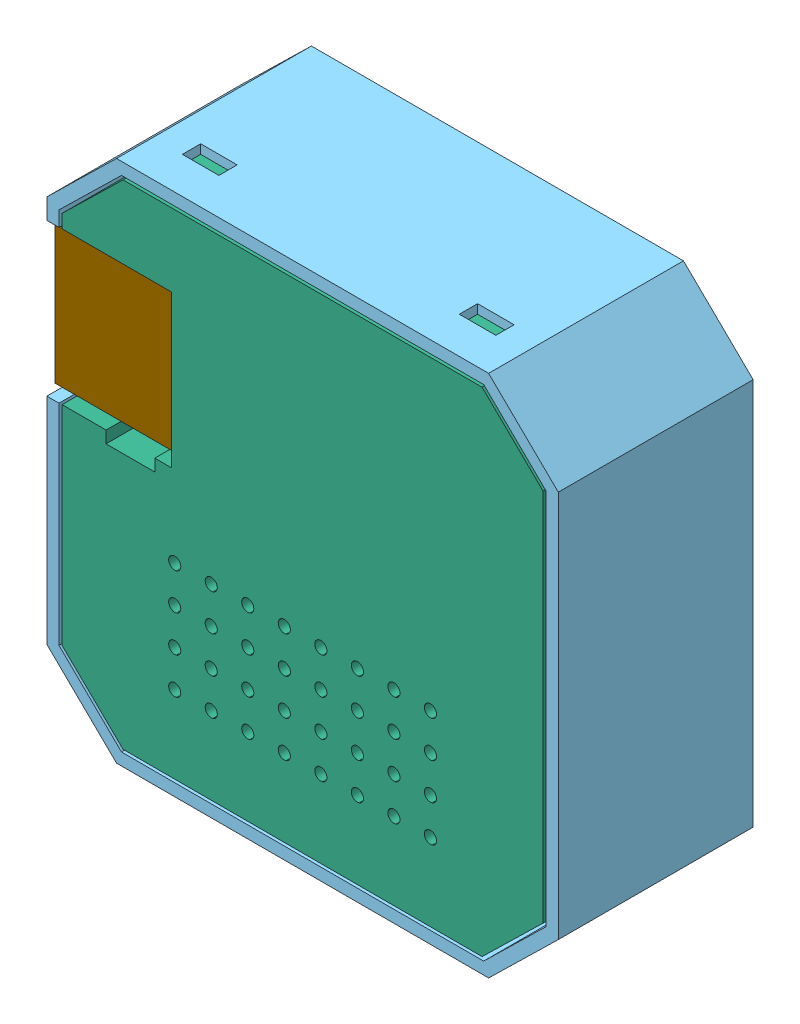
SolidWorks assembly UP-Buzzer-asm, configuration Default. Lengths in mm.
Overall size (42.12 43 16).
101 component instances, 61 part files, 8 mates.
Components (placement in the parent):
- UP1-Controller2040_V00.02.step-1: UP1-Controller2040_V00.02.step [Default] at (23.1746 53.0098 30.1469) size (40.62 22.3 14.2)
  - Board_Geoms_d6bd.step-1: Board_Geoms_d6bd.step [Default] at origin size (39 17.6 1.6)
    - Pcb_d6bd.step-1: Pcb_d6bd.step [Default] at (-120 80 0) size (39 17.6 1.6)
    - PCB_Sketch_d6bd.step-1: PCB_Sketch_d6bd.step [Default] at origin
  - Step_Models_d6bd.step-1: Step_Models_d6bd.step [Default] at origin size (39.5 21.08 14.2)
    - Top_d6bd.step-1: Top_d6bd.step [Default] at origin size (39.5 21.08 13.2)
      - J102_PinHeader_1x20_P127mm_Horizontal_60EE9F63.step-1: J102_PinHeader_1x20_P127mm_Horizontal_60EE9F63.step [Default] at (6.85 -37.8 -0.7) x (0 -1 0) z (0 0 1) size (5.7 25.4 4.5)
      - R111_R_0603_1608Metric_6205EFC4.step-1: R111_R_0603_1608Metric_6205EFC4.step [Default] at (-11 -34.6 0) x (0 1 0) z (0 0 1) size (1.6 0.8 0.45)
      - R112_R_0603_1608Metric_6205EFD5.step-1: R112_R_0603_1608Metric_6205EFD5.step [Default] at (-9.4 -34.6 0) x (0 1 0) z (0 0 1) size (1.6 0.8 0.45)
      - GN100_NanoBCU_V00.10_wo_headers_60EECF29.step-1: GN100_NanoBCU_V00.10_wo_headers_60EECF29.step [Default] at (0 -23.42 8.2) x (0 -1 0) z (0 0 1) size (18 18 8.65)
      - GN100_PinHeader_1x07_P254mm_Vertical_SMD_Pin1Left_60EECF29[2].step-1: GN100_PinHeader_1x07_P254mm_Vertical_SMD_Pin1Left_60EECF29[2].step [Default] at (-10.18 -24.72 0) x (0 1 0) z (0 0 1) size (5 17.78 9.3)
      - U102_SOT_23_5_6205ACC4.step-1: U102_SOT_23_5_6205ACC4.step [Default] at (-14.6 -34.5 0) x (0 1 0) z (0 0 1) size (2.8 2.9 1.55)
      - U103_SOT_23_6_6205A775.step-1: U103_SOT_23_6_6205A775.step [Default] at (-18.3 -34.5 0) x (0 1 0) z (0 0 1) size (2.8 2.9 1.55)
      - J100__243-212_60AF9738.step-1: J100__243-212_60AF9738.step [Default] at (-21.6186 -27.2 0.1) x (-1 0 0) z (0 0 1) size (10 12.61 10)
      - R114_R_0603_1608Metric_61113DD2.step-1: R114_R_0603_1608Metric_61113DD2.step [Default] at (-2.85 -34.25 0) x (-1 0 0) z (0 0 1) size (1.6 0.8 0.45)
      - R113_R_0603_1608Metric_61113DC1.step-1: R113_R_0603_1608Metric_61113DC1.step [Default] at (-2.855 -35.78 0) x (-1 0 0) z (0 0 1) size (1.6 0.8 0.45)
      - D100_D_SMA_60EECA5D.step-1: D100_D_SMA_60EECA5D.step [Default] at (-23 -24 0) size (5 2.7 2.22)
      - J101_PinHeader_1x08_P127mm_Vertical_60ECF3C0.step-1: J101_PinHeader_1x08_P127mm_Vertical_60ECF3C0.step [Default] at (6.83 -26.74 0) size (2.1 10.16 6.3)
    - Bot_d6bd.step-1: Bot_d6bd.step [Default] at origin size (33.8 14.77 2.55)
      - R109_R_0603_1608Metric_60F57743.step-1: R109_R_0603_1608Metric_60F57743.step [Default] at (-19.65 -36.325 -1.6) x (0 1 0) z (0 0 -1) size (1.6 0.8 0.45)
      - R110_R_0603_1608Metric_60F57732.step-1: R110_R_0603_1608Metric_60F57732.step [Default] at (-16.95 -35.425 -1.6) x (-1 0 0) z (0 0 -1) size (1.6 0.8 0.45)
      - R106_R_0402_1005Metric_60F519DA.step-1: R106_R_0402_1005Metric_60F519DA.step [Default] at (5.05 -33 -1.6) x (0 -1 0) z (0 0 -1) size (1 0.5 0.35)
      - U100_QFN-56-1EP_7x7mm_Pitch0.4mm_60ECE89B.step-1: U100_QFN-56-1EP_7x7mm_Pitch0.4mm_60ECE89B.step [Default] at (-6 -28.5 -1.6) x (0 -1 0) z (0 0 -1) size (7 7 0.92)
      - R115_R_0603_1608Metric_60ECF916.step-1: R115_R_0603_1608Metric_60ECF916.step [Default] at (2.5 -34.75 -1.6) x (1 0 0) z (0 0 -1) size (1.6 0.8 0.45)
      - R116_R_0603_1608Metric_60B1282C.step-1: R116_R_0603_1608Metric_60B1282C.step [Default] at (2.5 -36.25 -1.6) x (1 0 0) z (0 0 -1) size (1.6 0.8 0.45)
      - U101_SSOP_8_525x524mm_P127mm_60EDBF3D.step-1: U101_SSOP_8_525x524mm_P127mm_60EDBF3D.step [Default] at (-17.25 -28.25 -1.6) x (0 -1 0) z (0 0 -1) size (8.22 5.24 1.6)
      - Y100_Crystal_SMD_3225-4Pin_3.2x2.5mm_60EEB131.step-1: Y100_Crystal_SMD_3225-4Pin_3.2x2.5mm_60EEB131.step [Default] at (3.98 -26.43 -1.6) x (0 -1 0) z (0 0 -1) size (3.2 2.5 0.64)
      - SW100_SKRPACE010_v4_60ED873A.step-1: SW100_SKRPACE010_v4_60ED873A.step [Default] at (-25.8 -26.6 -1.6) x (1 0 0) z (0 1 0) size (4.89 2.55 3.2)
      - R105_C_0402_1005Metric_60ECE7EE.step-1: R105_C_0402_1005Metric_60ECE7EE.step [Default] at (-0.25 -32.25 -1.6) x (1 0 0) z (0 0 -1) size (1 0.5 0.5)
      - R108_C_0402_1005Metric_60ECE7DF.step-1: R108_C_0402_1005Metric_60ECE7DF.step [Default] at (-12 -31 -1.6) x (1 0 0) z (0 0 -1) size (1 0.5 0.5)
      - R107_C_0402_1005Metric_60ECE7D0.step-1: R107_C_0402_1005Metric_60ECE7D0.step [Default] at (-12 -30 -1.6) x (1 0 0) z (0 0 -1) size (1 0.5 0.5)
      - R102_C_0402_1005Metric_60ECE7C1.step-1: R102_C_0402_1005Metric_60ECE7C1.step [Default] at (1.62 -27.51 -1.6) x (0 1 0) z (0 0 -1) size (1 0.5 0.5)
      - R103_C_0402_1005Metric_60ECE7B2.step-1: R103_C_0402_1005Metric_60ECE7B2.step [Default] at (-0.25 -33.5 -1.6) x (1 0 0) z (0 0 -1) size (1 0.5 0.5)
      - R104_C_0402_1005Metric_60ECE7A3.step-1: R104_C_0402_1005Metric_60ECE7A3.step [Default] at (-10.71 -24.72 -1.6) x (0 -1 0) z (0 0 -1) size (1 0.5 0.5)
      - R101_R_0402_1005Metric_60ECE794.step-1: R101_R_0402_1005Metric_60ECE794.step [Default] at (-28.25 -28 -1.6) x (0 1 0) z (0 0 -1) size (1 0.5 0.35)
      - D101_LED_0603_1608Metric_60EEBCB9.step-1: D101_LED_0603_1608Metric_60EEBCB9.step [Default] at (-27.5 -32.5 -1.6) x (-1 0 0) z (0 0 -1) size (1.6 0.8 1.1)
      - C115_C_0402_1005Metric_60ECE606.step-1: C115_C_0402_1005Metric_60ECE606.step [Default] at (-9 -23.26 -1.6) x (0 1 0) z (0 0 -1) size (1 0.5 0.5)
      - C114_C_0402_1005Metric_60ECE5F7.step-1: C114_C_0402_1005Metric_60ECE5F7.step [Default] at (-4.5 -23 -1.6) x (0 1 0) z (0 0 -1) size (1 0.5 0.5)
      - C113_C_0402_1005Metric_60ECE5E8.step-1: C113_C_0402_1005Metric_60ECE5E8.step [Default] at (-0.25 -28.25 -1.6) x (1 0 0) z (0 0 -1) size (1 0.5 0.5)
      - C112_C_0402_1005Metric_60ECE5D9.step-1: C112_C_0402_1005Metric_60ECE5D9.step [Default] at (-4.925 -33.85 -1.6) x (0 -1 0) z (0 0 -1) size (1 0.5 0.5)
      - C111_C_0402_1005Metric_60EECFE7.step-1: C111_C_0402_1005Metric_60EECFE7.step [Default] at (-9.775 -34.15 -1.6) x (-1 0 0) z (0 0 -1) size (1 0.5 0.5)
      - C110_C_0402_1005Metric_60ECE5AC.step-1: C110_C_0402_1005Metric_60ECE5AC.step [Default] at (-12 -29 -1.6) x (-1 0 0) z (0 0 -1) size (1 0.5 0.5)
      - C120_C_0402_1005Metric_60EECFBD.step-1: C120_C_0402_1005Metric_60EECFBD.step [Default] at (-9.775 -33.15 -1.6) x (-1 0 0) z (0 0 -1) size (1 0.5 0.5)
      - C130_C_0402_1005Metric_60EEB37E.step-1: C130_C_0402_1005Metric_60EEB37E.step [Default] at (-11.075 -32 -1.6) x (-1 0 0) z (0 0 -1) size (1 0.5 0.5)
      - C131_C_0402_1005Metric_60ED72AC.step-1: C131_C_0402_1005Metric_60ED72AC.step [Default] at (-0.25 -29.25 -1.6) x (1 0 0) z (0 0 -1) size (1 0.5 0.5)
      - C132_C_0402_1005Metric_60ECE570.step-1: C132_C_0402_1005Metric_60ECE570.step [Default] at (-12 -28 -1.6) x (-1 0 0) z (0 0 -1) size (1 0.5 0.5)
      - C109_C_0805_2012Metric_60ECE561.step-1: C109_C_0805_2012Metric_60ECE561.step [Default] at (-1.85 -22.98 -1.6) x (1 0 0) z (0 0 -1) size (2 1.25 1.25)
      - C105_C_0402_1005Metric_60ECE550.step-1: C105_C_0402_1005Metric_60ECE550.step [Default] at (-0.25 -31.25 -1.6) x (-1 0 0) z (0 0 -1) size (1 0.5 0.5)
      - C101_C_0402_1005Metric_60ECE541.step-1: C101_C_0402_1005Metric_60ECE541.step [Default] at (3.98 -29.04 -1.6) x (1 0 0) z (0 0 -1) size (1 0.5 0.5)
      - C102_C_0402_1005Metric_60ECE532.step-1: C102_C_0402_1005Metric_60ECE532.step [Default] at (3.98 -23.79 -1.6) x (-1 0 0) z (0 0 -1) size (1 0.5 0.5)
      - C103_C_0402_1005Metric_60ECE523.step-1: C103_C_0402_1005Metric_60ECE523.step [Default] at (-19.2 -33.5 -1.6) x (1 0 0) z (0 0 -1) size (1 0.5 0.5)
- UP-Buzzer-PCB.step-1: UP-Buzzer-PCB.step [Default] at (-6.9323 10.7878 29.4969) x (0 -1 0) z (0 0 1) size (20.62 38.86 15.85)
  - Board.step-1: Board.step [Default] at origin size (18.8 38.86 1.69)
    - Open CASCADE STEP translator 7.5 1.1.1.step-1: Open CASCADE STEP translator 7.5 1.1.1.step [Default] at (0 0 -1.6916) size (18.8 38.86 1.69)
  - U2.step-1: U2.step [Default] at origin size (11.61 5.99 15.65) (hidden)
    - 6360212480.step-1: 6360212480.step [Default] at (3.3148 8.204 0) x (1 0 0) z (0 0 1) size (11.61 5.99 15.65)
  - R9.step-1: R9.step [Default] at origin size (0.81 1.6 0.71) (hidden)
    - 6360212240.step-1: 6360212240.step [Default] at (16.129 10.922 -1.6916) x (0 -1 0) z (0 0 -1) size (1.6 0.81 0.71)
  - R8.step-1: R8.step [Default] at origin size (0.81 1.6 0.71) (hidden)
    - 6360212240.step-1: 6360212240.step [Default] at (14.605 10.922 -1.6916) x (0 -1 0) z (0 0 -1) size (1.6 0.81 0.71)
  - R7.step-1: R7.step [Default] at origin size (0.81 1.6 0.71) (hidden)
    - 6360212240.step-1: 6360212240.step [Default] at (13.081 10.922 -1.6916) x (0 -1 0) z (0 0 -1) size (1.6 0.81 0.71)
  - R6.step-1: R6.step [Default] at origin size (0.81 1.6 0.71) (hidden)
    - 6360212240.step-1: 6360212240.step [Default] at (11.557 10.922 -1.6916) x (0 -1 0) z (0 0 -1) size (1.6 0.81 0.71)
  - R5.step-1: R5.step [Default] at origin size (0.81 1.6 0.71) (hidden)
    - 6360212240.step-1: 6360212240.step [Default] at (10.033 10.922 -1.6916) x (0 -1 0) z (0 0 -1) size (1.6 0.81 0.71)
  - R4.step-1: R4.step [Default] at origin size (0.81 1.6 0.71) (hidden)
    - 6360212240.step-1: 6360212240.step [Default] at (8.509 10.922 -1.6916) x (0 -1 0) z (0 0 -1) size (1.6 0.81 0.71)
  - R3.step-1: R3.step [Default] at origin size (0.81 1.6 0.71) (hidden)
    - 6360212240.step-1: 6360212240.step [Default] at (6.985 10.922 -1.6916) x (0 -1 0) z (0 0 -1) size (1.6 0.81 0.71)
  - R2.step-1: R2.step [Default] at origin size (0.81 1.6 0.71) (hidden)
    - 6360212240.step-1: 6360212240.step [Default] at (5.461 10.922 -1.6916) x (0 -1 0) z (0 0 -1) size (1.6 0.81 0.71)
  - Q1.step-1: Q1.step [Default] at origin size (10.44 20.35 4) (hidden)
    - 6360211360.step-1: 6360211360.step [Default] at (9.906 23.876 -1.6916) x (-1 0 0) z (0 0 -1) size (10.44 20.35 4)
  - C2.step-1: C2.step [Default] at origin size (1.45 2.2 1.4) (hidden)
    - 6437173456.step-1: 6437173456.step [Default] at (17.653 10.922 -3.0916) size (1.45 2.2 1.4)
      - Extruded.step-1: Extruded.step [Default] at origin size (1.45 2.2 1.4)
  - C1.step-1: C1.step [Default] at origin size (2.2 1.45 1.4) (hidden)
    - 6437173616.step-1: 6437173616.step [Default] at (9.64 16.383 0) size (2.2 1.45 1.4)
      - Extruded-0.step-1: Extruded-0.step [Default] at origin size (2.2 1.45 1.4)
  - R1.step-1: R1.step [Default] at origin size (0.81 1.6 0.71)
    - 6360212240.step-1: 6360212240.step [Default] at (5.842 34.036 0) x (0 1 0) z (0 0 1) size (1.6 0.81 0.71)
  - P1.step-1: P1.step [Default] at origin size (4.66 25.8 4.6)
    - pinheader_20pin_127mm_pitch.step-1: pinheader_20pin_127mm_pitch.step [Default] at (2.6781 37.5919 0) x (0 -1 0) z (0 0 1) size (25.8 4.66 4.6)
  - LS1.step-1: LS1.step [Default] at origin size (8.74 8.74 3)
    - 6437175616.step-1: 6437175616.step [Default] at (9.652 23.114 0) size (8.74 8.74 3)
      - Extruded-1.step-1: Extruded-1.step [Default] at origin size (8.74 8.74 3)
  - CR1.step-1: CR1.step [Default] at origin size (3.85 1.36 0.82)
    - SOD123_DIO.step-1: SOD123_DIO.step [Default] at (7.8741 30.2261 0) x (-1 0 0) z (0 0 1) size (3.85 1.36 0.82)
    - 6360213120.step-1: 6360213120.step [Default] at (7.874 30.226 0) x (-1 0 0) z (0 0 1) size (3.85 1.36 0.82)
  - U1.step-1: U1.step [Default] at origin size (2.64 3.08 1.14)
    - 6360210800.step-1: 6360210800.step [Default] at (9.271 34.036 0) x (0 -1 0) z (0 0 1) size (3.08 2.64 1.14)
  - C3.step-1: C3.step [Default] at origin size (2.2 1.45 1.4) (hidden)
    - 6437173616.step-1: 6437173616.step [Default] at (9.64 14.605 0) size (2.2 1.45 1.4)
      - Extruded-0.step-1: Extruded-0.step [Default] at origin size (2.2 1.45 1.4)
  - R11.step-1: R11.step [Default] at origin size (1.6 0.81 0.71) (hidden)
    - 6360210720.step-1: 6360210720.step [Default] at (9.652 12.954 0) x (-1 0 0) z (0 0 1) size (1.6 0.81 0.71)
  - U3.step-1: U3.step [Default] at origin size (2.79 2.9 1) (hidden)
    - 6360210960.step-1: 6360210960.step [Default] at (5.842 15.748 0) x (1 0 0) z (0 0 1) size (2.79 2.9 1)
- UP-Buzzer-housing-1: UP-Buzzer-housing [Default] at (12.6746 12.0098 25.0469) x (0 1 0) z (1 0 0) size (43 16 42)
- UP-Buzzer-housing-upper-1: UP-Buzzer-housing-upper [Default] at (12.6746 12.0098 34.0469) x (0 1 0) z (1 0 0) size (42.1 11 39.5)
Mates (geometry in assembly coordinates):
- Distance8: distance = 1.1 mm anti-aligned: plane of UP1-Controller2040_V00.02.step-1/Step_Models_d6bd.step-1/Top_d6bd.step-1/J102_PinHeader_1x20_P127mm_Horizontal_60EE9F63.step-1 through (17.9596 13.7098 30.4969) normal (0 -1 0); plane of UP-Buzzer-PCB.step-1/P1.step-1/pinheader_20pin_127mm_pitch.step-1 through (30.6596 12.6098 31.2969) normal (0 1 0)
- Coincident23: coincident anti-aligned: plane of UP1-Controller2040_V00.02.step-1/Step_Models_d6bd.step-1/Top_d6bd.step-1/J102_PinHeader_1x20_P127mm_Horizontal_60EE9F63.step-1 through (30.2246 15.4098 30.6969) normal (0 0 1); plane of UP-Buzzer-PCB.step-1/P1.step-1/pinheader_20pin_127mm_pitch.step-1 through (30.1596 9.6098 30.6969) normal (0 0 -1)
- Distance9: distance = 0.5 mm anti-aligned: plane of UP1-Controller2040_V00.02.step-1/Board_Geoms_d6bd.step-1/Pcb_d6bd.step-1 through (-1.8254 32.0098 30.1469) normal (0 1 0); plane of UP-Buzzer-housing-1 through (27.5443 32.5098 26.0469) normal (0 -1 0)
- Distance10: distance = 0.5 mm anti-aligned: plane of UP1-Controller2040_V00.02.step-1/Board_Geoms_d6bd.step-1/Pcb_d6bd.step-1 through (32.1746 27.0098 30.1469) normal (1 0 0); plane of UP-Buzzer-housing-1 through (32.6746 -3.4792 26.0469) normal (-1 0 0)
- Coincident35: coincident anti-aligned: plane of UP1-Controller2040_V00.02.step-1/Step_Models_d6bd.step-1/Bot_d6bd.step-1/SW100_SKRPACE010_v4_60ED873A.step-1 through (-0.3254 28.0098 26.0469) normal (0 0 -1); plane of UP-Buzzer-housing-1 through (12.6746 12.0098 26.0469) normal (0 0 1)
- Distance5: distance = 0.25 mm anti-aligned: plane of UP-Buzzer-housing-1 through (32.6746 -3.4792 26.0469) normal (-1 0 0); plane of UP-Buzzer-housing-upper-1 through (32.4246 27.3723 41.0469) normal (1 0 0)
- Distance6: distance = 0.25 mm anti-aligned: plane of UP-Buzzer-housing-upper-1 through (27.4134 32.2598 41.0469) normal (0 1 0); plane of UP-Buzzer-housing-1 through (27.5443 32.5098 26.0469) normal (0 -1 0)
- Coincident53: coincident aligned: plane of UP-Buzzer-housing-1 through (12.6746 12.0098 41.0469) normal (0 0 1); plane of UP-Buzzer-housing-upper-1 through (12.6746 12.0098 41.0469) normal (0 0 1)
